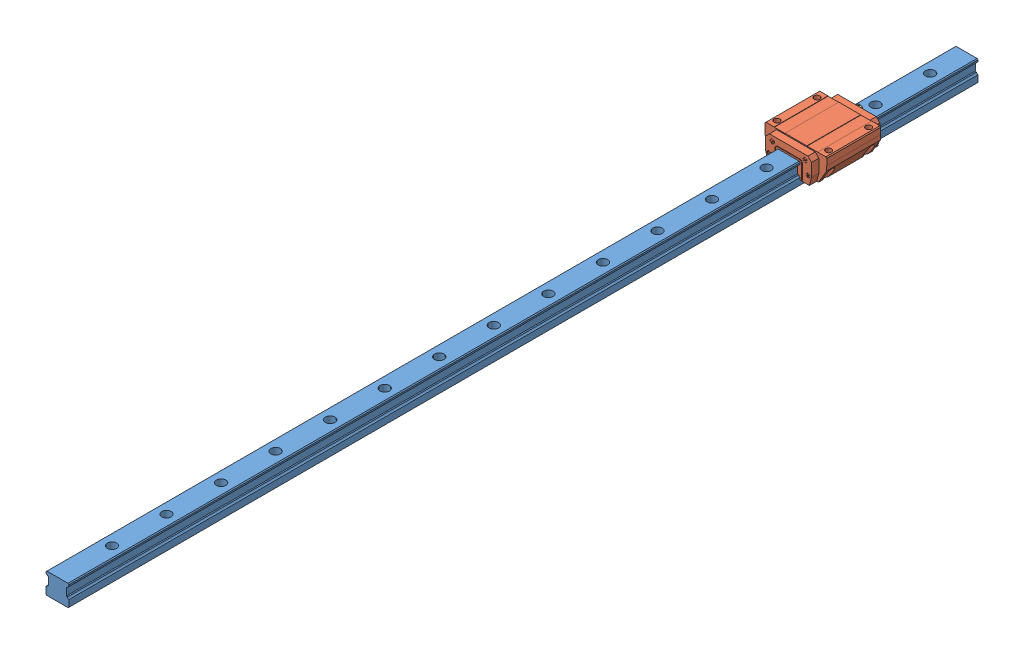
SolidWorks assembly NH65EA_B1_T0_1500_C5_W1_E75_0_FS, configuration Valor predeterminado. Lengths in mm.
Overall size (170 85 2500).
4 component instances, 3 part files, 2 mates.
Components (placement in the parent):
- NH65 Rail-1: NH65 Rail [Valor predeterminado] at origin size (63 58 2500)
- NH65EA_AMBLY_STD-1: NH65EA_AMBLY_STD [Valor predeterminado] at (0 58 469.2121) x (0 0 -1) z (1 0 0) size (203.31 71 170)
  - NH65EA_STD-1: NH65EA_STD [Valor predeterminado] at origin size (188 71 170)
  - B-PT18_1-1: B-PT18_1 [Valor predeterminado] at (171.5 14.0027 -0.0004) x (0 -1 0) z (1 0 0) size (11.52 17.05 22.81)
Mates (geometry in assembly coordinates):
- Coincidente2: coincident anti-aligned: plane of NH65 Rail-1 through (31.5 58 2500) normal (0 1 0); plane of NH65EA_AMBLY_STD-1/NH65EA_STD-1 through (0 58 321.2121) normal (0 -1 0)
- Largura1: width anti-aligned: plane of NH65EA_AMBLY_STD-1/NH65EA_STD-1 through (-24.5 58 321.2121) normal (1 0 0); plane of NH65EA_AMBLY_STD-1/NH65EA_STD-1 through (24.5 58 321.2121) normal (-1 0 0); plane of NH65 Rail-1 through (24.5 25.5979 2500) normal (1 0 0); plane of NH65 Rail-1 through (-24.5 46.3997 2500) normal (-1 0 0)
